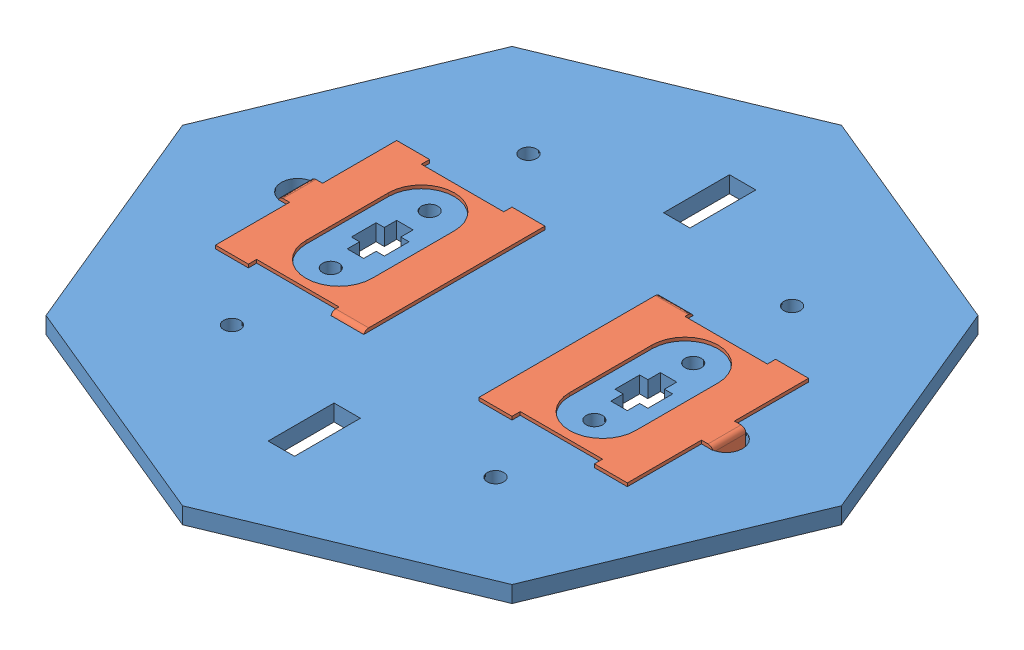
SolidWorks assembly 12ax7_mica_2, configuration Default. Lengths in mm.
Overall size (20 1.5 20).
3 component instances, 2 part files, 0 mates.
Components (placement in the parent):
- mica2-1: mica2 [Default] at origin size (20 0.5 20)
- cathode_end-1: cathode_end [Default] at (4 0.5 0) x (1 0 0) z (0 -1 0) size (4.85 6.8 1.5)
- cathode_end-2: cathode_end [Default] at (-4 0.5 0) x (-1 0 0) z (0 -1 0) size (4.85 6.8 1.5)
